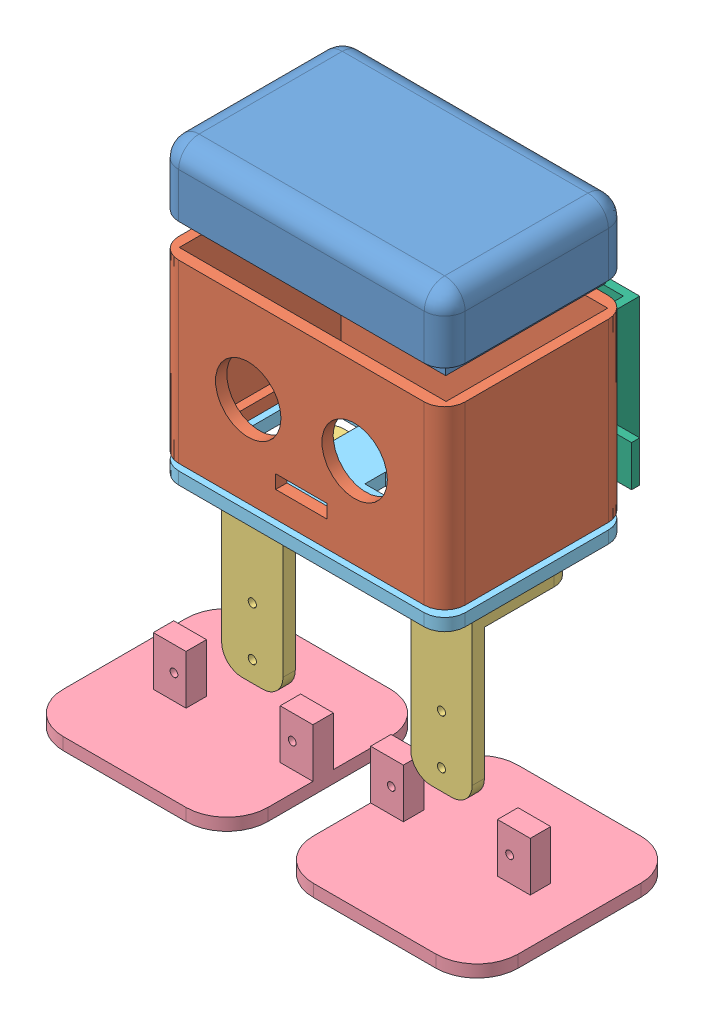
SolidWorks assembly 装配体1, configuration 默认. Lengths in mm.
Overall size (111.6 128.87 72.41).
8 component instances, 6 part files, 13 mates.
Components (placement in the parent):
- 额头-1: 额头 [默认] at (-6.3922 8.5011 70) x (-1 0 0) z (0 0 1) size (70 19 45)
- 身体上-1: 身体上 [默认] at (-6.3922 -42.6736 70) size (70 43 45)
- 腿-1: 腿 [默认] at (-36.8922 -91.2045 78.5) size (15 40 25)
- 腿-2: 腿 [默认] at (9.1078 -91.2045 78.2863) size (15 40 25)
- 脚-1: 脚 [默认] at (-36.3796 -104.3715 80.706) size (50 15 50)
- 脚-2: 脚 [默认] at (25.2173 -104.3715 81.2042) x (-1 0 0) z (0 0 -1) size (50 15 50)
- 身体下-1: 身体下 [默认] at (-6.3922 -47.2775 70) size (70 3 45)
- 电池盖板-2: 电池盖板 [默认] at (-22.9678 -39.6679 35.7961) x (-1 0 0) z (0 0 -1) size (67.96 30 12)
Mates (geometry in assembly coordinates):
- 平行1: parallel anti-aligned: plane of 额头-1 through (28.6078 23.5011 92.5) normal (1 0 0); plane of 身体上-1 through (-41.3922 -39.6736 47.5) normal (-1 0 0)
- 重合2: coincident aligned: plane of 额头-1 through (-41.3922 23.5011 92.5) normal (-1 0 0); plane of 身体上-1 through (-41.3922 -39.6736 47.5) normal (-1 0 0)
- 重合3: coincident aligned: plane of 额头-1 through (28.6078 23.5011 92.5) normal (0 0 1); plane of 身体上-1 through (-41.3922 -39.6736 92.5) normal (0 0 1)
- 平行2: parallel aligned: plane of 身体上-1 through (-41.3922 -39.6736 47.5) normal (0 0 -1); plane of 身体下-1 through (-41.3922 -44.2775 47.5) normal (0 0 -1)
- 重合4: coincident aligned: plane of 身体上-1 through (-41.3922 -39.6736 47.5) normal (-1 0 0); plane of 身体下-1 through (-41.3922 -44.2775 47.5) normal (-1 0 0)
- 平行3: parallel aligned: plane of 身体上-1 through (-41.3922 -39.6736 47.5) normal (0 0 -1); plane of 身体下-1 through (-41.3922 -44.2775 47.5) normal (0 0 -1)
- 平行4: parallel aligned: plane of 身体上-1 through (-41.3922 -39.6736 47.5) normal (0 0 -1); plane of 身体下-1 through (-41.3922 -44.2775 47.5) normal (0 0 -1)
- 重合6: coincident aligned: plane of 身体上-1 through (-41.3922 -39.6736 47.5) normal (0 0 -1); plane of 身体下-1 through (-41.3922 -44.2775 47.5) normal (0 0 -1)
- 重合7: coincident aligned: plane of 腿-1 through (-36.8922 -51.2045 81.5) normal (0 1 0); plane of 腿-2 through (9.1078 -51.2045 81.2863) normal (0 1 0)
- 重合8: coincident aligned: plane of 脚-1 through (-21.3796 -104.3715 65.706) normal (0 -1 0); plane of 脚-2 through (10.2173 -104.3715 96.2042) normal (0 -1 0)
- 重合9: coincident anti-aligned: plane of 腿-1 through (-36.8922 -86.2045 81.5) normal (-1 0 0); plane of 身体下-1 through (-36.8922 -54.2775 58.5) normal (1 0 0)
- 重合10: coincident anti-aligned: plane of 腿-1 through (-31.8922 -86.2045 81.5) normal (0 0 1); plane of 身体下-1 through (-36.8922 -54.2775 81.5) normal (0 0 -1)
- 重合12: coincident anti-aligned: plane of 腿-2 through (24.1078 -86.2045 81.2863) normal (1 0 0); plane of 身体下-1 through (24.1078 -54.2775 58.5) normal (-1 0 0)
